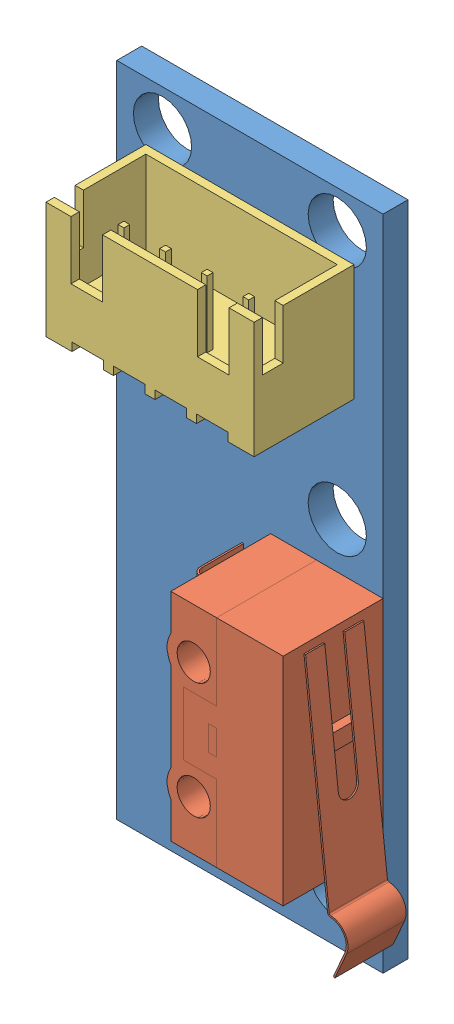
SolidWorks assembly Endstop_Microswitch_1A125VAC_DesjgnByMakerbot, configuration Défaut. Lengths in mm.
Overall size (18.65 39.5 8).
3 component instances, 3 part files, 7 mates.
Components (placement in the parent):
- PCB^Endstop_Microswitch_1A125VAC_DesjgnByMakerbot-1: PCB^Endstop_Microswitch_1A125VAC_DesjgnByMakerbot [Défaut] at origin size (16 39.5 1.5) (virtual)
- Microswitch_1A_125vAC(seul)-1: Microswitch_1A_125vAC(seul) [Défaut] at (0 -6.75 4.5) size (11.12 16.44 8)
- Connecteur^Endstop_Microswitch_1A125VAC_DesjgnByMakerbot-1: Connecteur^Endstop_Microswitch_1A125VAC_DesjgnByMakerbot [Défaut] at (0 0 1.5) size (12.5 7.35 8) (virtual)
Mates (geometry in assembly coordinates):
- Coïncidente4: coincident anti-aligned: plane of PCB^Endstop_Microswitch_1A125VAC_DesjgnByMakerbot-1 through (0 0 1.5) normal (0 0 1); plane of Microswitch_1A_125vAC(seul)-1 through (0 -6.75 1.5) normal (0 0 -1)
- Distance1: distance = 6.5 mm aligned: plane of Microswitch_1A_125vAC(seul)-1 through (-4 -13.25 7.5) normal (0 -1 0); plane of PCB^Endstop_Microswitch_1A125VAC_DesjgnByMakerbot-1 through (-16 -19.75 1.5) normal (0 -1 0)
- Coïncidente7: coincident aligned: plane of PCB^Endstop_Microswitch_1A125VAC_DesjgnByMakerbot-1 through (0 19.75 1.5) normal (1 0 0); plane of Microswitch_1A_125vAC(seul)-1 through (0 -0.25 7.5) normal (1 0 0)
- Sur place2: in place: plane of PCB^Endstop_Microswitch_1A125VAC_DesjgnByMakerbot-1 through (0 0 1.5) normal (0 0 1); plane of Connecteur^Endstop_Microswitch_1A125VAC_DesjgnByMakerbot-1 through (0 0 1.5) normal (0 0 1); moOrthogonalPlaneRef_w of PCB^Endstop_Microswitch_1A125VAC_DesjgnByMakerbot-1 through (0 0 1.5) normal (0 0 1); plane of Connecteur^Endstop_Microswitch_1A125VAC_DesjgnByMakerbot-1 through (0 0 1.5) normal (0 1 0); plane of PCB^Endstop_Microswitch_1A125VAC_DesjgnByMakerbot-1 through (0 0 1.5) normal (0 0 1); plane of Connecteur^Endstop_Microswitch_1A125VAC_DesjgnByMakerbot-1 through (0 0 1.5) normal (1 0 0); plane of PCB^Endstop_Microswitch_1A125VAC_DesjgnByMakerbot-1 through (0 0 1.5) normal (0 0 1); unknown of Connecteur^Endstop_Microswitch_1A125VAC_DesjgnByMakerbot-1
- Coïncidente8: coincident aligned: 
- Coïncidente9: coincident aligned: plane of PCB^Endstop_Microswitch_1A125VAC_DesjgnByMakerbot-1 through (0 0 1.5) normal (0 1 0); plane of Connecteur^Endstop_Microswitch_1A125VAC_DesjgnByMakerbot-1 through (0 0 1.5) normal (0 1 0)
- Coïncidente10: coincident anti-aligned: plane of PCB^Endstop_Microswitch_1A125VAC_DesjgnByMakerbot-1 through (0 0 1.5) normal (-1 0 0); plane of Connecteur^Endstop_Microswitch_1A125VAC_DesjgnByMakerbot-1 through (0 0 1.5) normal (1 0 0)
